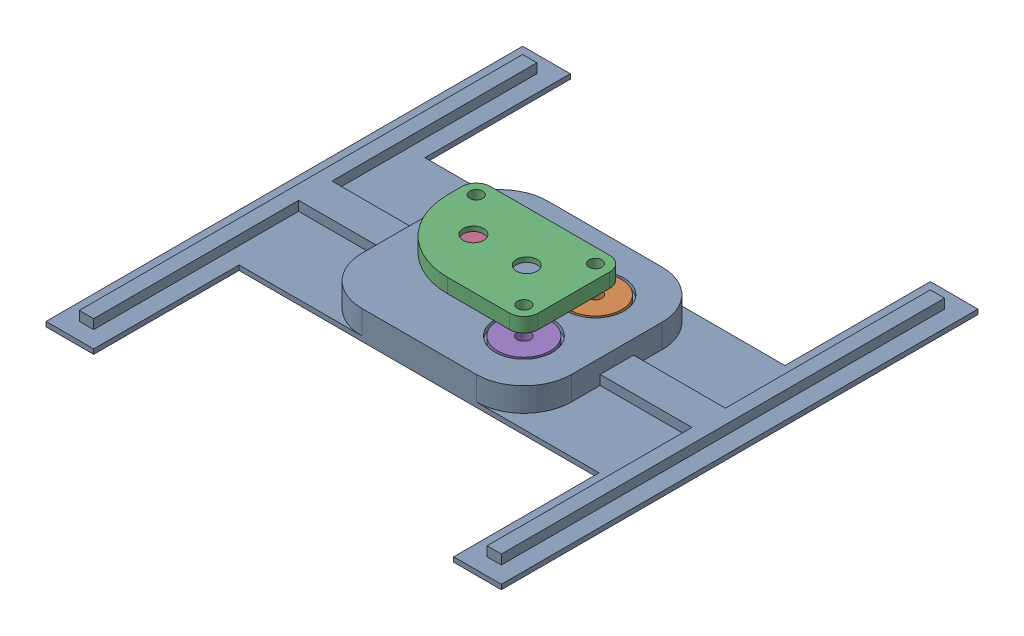
SolidWorks assembly jig full, configuration Default. Lengths in mm.
Overall size (95.53 11.64 100).
5 component instances, 3 part files, 9 mates.
Components (placement in the parent):
- base jig-1: base jig [Default] at (9.5175 18.6369 15.4634) size (95.53 6 100)
- plug-1: plug [Default] at (20.5062 24.6369 13.0499) x (-0.837169 0 -0.546944) z (-0.546944 0 0.837169) size (11 1.96 11)
- valve jig-1: valve jig [Default] at (2.4112 27.2739 20.5499) size (31 3 21)
- plug-2: plug [Default] at (-4.4938 24.6369 13.0499) x (-0.837169 0 -0.546944) z (-0.546944 0 0.837169) size (11 1.96 11)
- plug-3: plug [Default] at (20.5062 24.6369 28.0499) x (-0.60547 0 -0.795868) z (-0.795868 0 0.60547) size (11 1.96 11)
Mates (geometry in assembly coordinates):
- Coincident2: coincident anti-aligned: plane of base jig-1 through (20.5062 23.6369 13.0499) normal (0 1 0); plane of plug-1 through (20.5062 23.6369 13.0499) normal (0 -1 0)
- Concentric1: concentric anti-aligned: cylinder of base jig-1 through (20.5062 10.8587 13.0499) axis (0 1 0) radius 2.75; circle of plug-1
- Concentric2: concentric anti-aligned: cylinder of base jig-1 through (20.5062 23.6369 28.0499) axis (0 1 0) radius 6; cylinder of plug-3 through (20.5062 29.6369 28.0499) axis (0 -1 0) radius 1.3743
- Coincident3: coincident anti-aligned: plane of base jig-1 through (20.5062 23.6369 28.0499) normal (0 1 0); plane of plug-3 through (20.5062 23.6369 28.0499) normal (0 -1 0)
- Coincident4: coincident anti-aligned: plane of base jig-1 through (-4.4938 23.6369 13.0499) normal (0 1 0); plane of plug-2 through (-4.4938 23.6369 13.0499) normal (0 -1 0)
- Concentric3: concentric anti-aligned: cylinder of base jig-1 through (-4.4938 23.6369 13.0499) axis (0 1 0) radius 6; circle of plug-2
- Concentric4: concentric aligned: cylinder of valve jig-1 through (20.5062 30.2739 28.0499) axis (0 -1 0) radius 1.35; cylinder of plug-3 through (20.5062 29.6369 28.0499) axis (0 -1 0) radius 1.3743
- Concentric5: concentric aligned: cylinder of plug-1 through (20.5062 29.6369 13.0499) axis (0 -1 0) radius 1.3743; cylinder of valve jig-1 through (20.5062 30.2739 13.0499) axis (0 -1 0) radius 1.35
- Parallel1: parallel anti-aligned: plane of base jig-1 through (22.5062 19.6369 11.0499) normal (0 1 0); plane of plug-1 through (20.5062 22.6769 13.0499) normal (0 -1 0)
